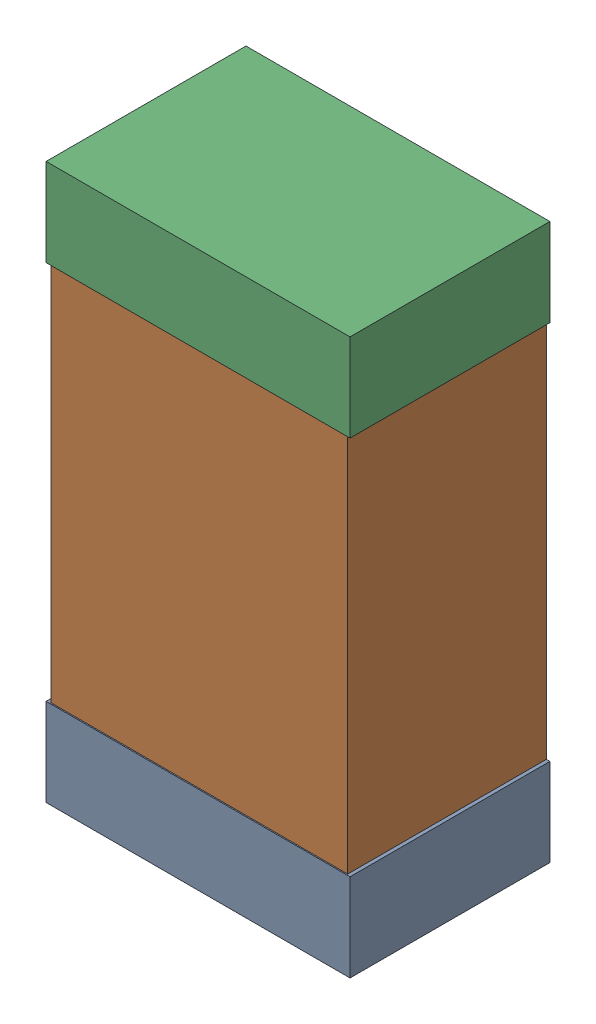
SolidWorks assembly ENTKanaloa_v2.0.0_Power, configuration Default. Lengths in mm.
Overall size (1.3 2.38 0.85).
6 component instances, 2 part files, 0 mates.
Components (placement in the parent):
- 330415056-1: 330415056 [Default] at (42.164 122.952 0) size (1.3 0.38 0.85)
  - Extruded_2-1: Extruded_2 [Default] at origin size (1.3 0.38 0.85)
- 352877008-1: 352877008 [Default] at (42.164 123.952 0) size (1.27 2.2 0.85)
  - Extruded_3-1: Extruded_3 [Default] at origin size (1.27 2.2 0.85)
- 330415056-2: 330415056 [Default] at (42.164 124.952 0) size (1.3 0.38 0.85)
  - Extruded_2-1: Extruded_2 [Default] at origin size (1.3 0.38 0.85)
